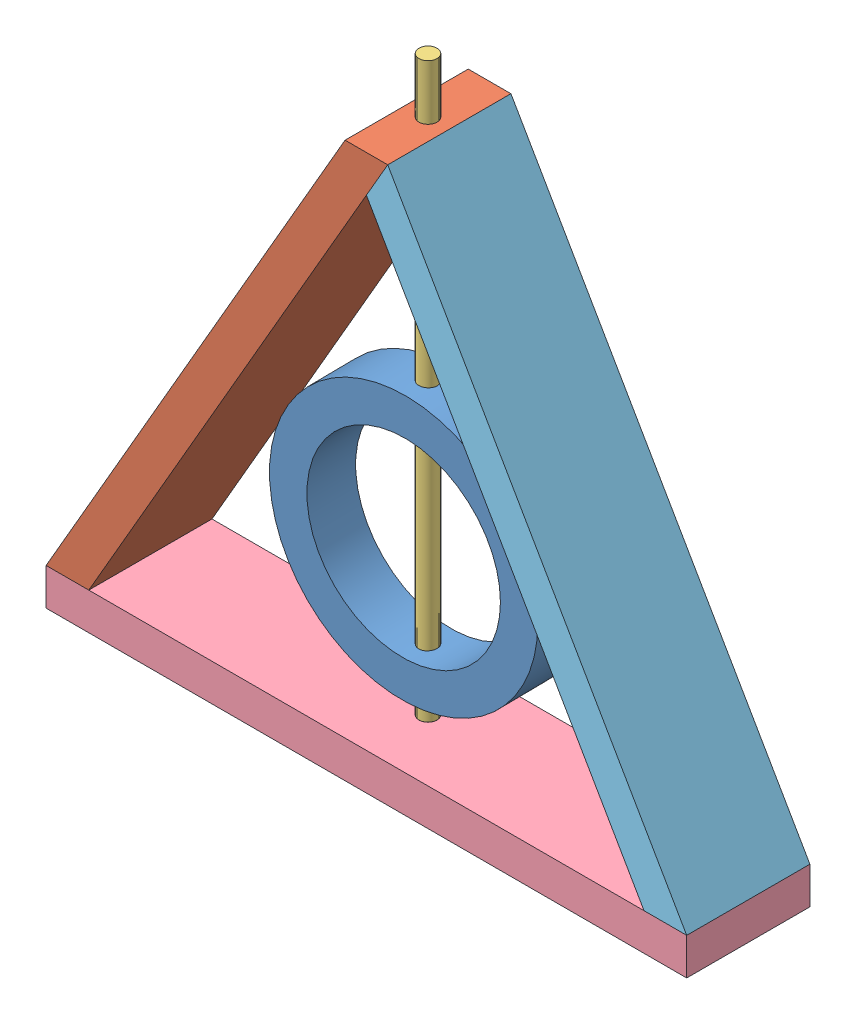
SolidWorks assembly Lamp_Assembly, configuration Default. Lengths in mm.
Overall size (330.2 314.33 63.5).
5 component instances, 5 part files, 4 mates.
Components (placement in the parent):
- Lamp_Center-1: Lamp_Center [Default] at (39.2473 100.076 116.2557) x (-0.999925 0 0.012241) z (-0.012241 0 -0.999925) size (136.65 136.65 25.4)
- Lamp-1: Lamp [Default] at (39.0918 0 71.8067) size (176.1 266.91 63.5)
- Lamp_Post-1: Lamp_Post [Default] at (39.0918 19.05 103.5567) size (9.32 295.28 9.32)
- Lamp_bottom-1: Lamp_bottom [Default] at (39.0918 0 71.8067) size (330.2 19.05 63.5)
- Lamp_Right-1: Lamp_Right [Default] at (121.6418 152.5058 71.8067) size (165.1 266.91 63.5)
Mates (geometry in assembly coordinates):
- Concentric2: concentric anti-aligned: cylinder of Lamp_Center-1 through (39.0918 25.4 103.5567) axis (0 1 0) radius 4.699; cylinder of Lamp_Post-1 through (39.0918 314.325 103.5567) axis (0 -1 0) radius 4.6609
- Coincident4: coincident: moEndPointRef_w of Lamp-1; moEndPointRef_w of Lamp_bottom-1
- Coincident5: coincident: moEndPointRef_w of Lamp-1; moEndPointRef_w of Lamp_Right-1
- Distance4: distance = 12.7 mm anti-aligned: cylinder of Lamp_Center-1 through (38.9364 100.076 90.8576) axis (0.012241 0 0.999925) radius 68.326; plane of Lamp_bottom-1 through (-126.0082 19.05 135.3067) normal (0 1 0)
